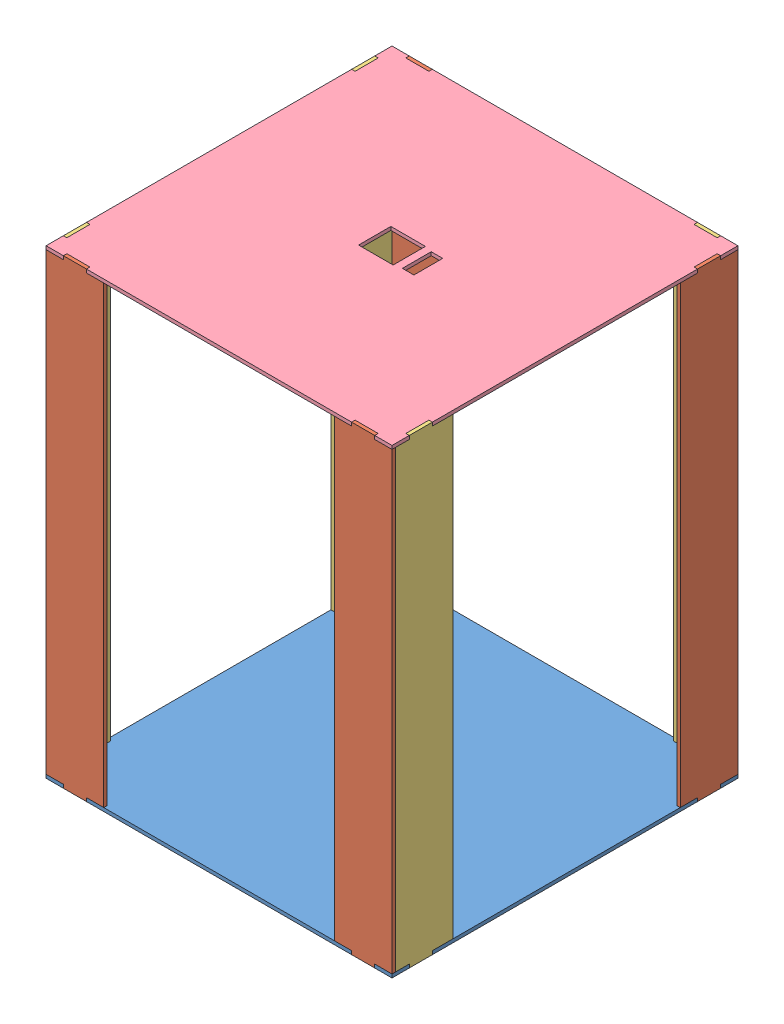
SolidWorks assembly Ensamblaje1Robotica, configuration Predeterminado. Lengths in mm.
Overall size (300 400 300).
10 component instances, 4 part files, 39 mates.
Components (placement in the parent):
- Base_Robotica-1: Base_Robotica [Predeterminado] at (-84.7591 -67.9143 450) size (300 3 300)
- Esquina_Robotica-1: Esquina_Robotica [Predeterminado] at (-84.7591 -64.9143 447) size (50 400 3)
- Esquina_Robotica2-1: Esquina_Robotica2 [Predeterminado] at (-81.7591 -64.9143 153) x (0 0 1) z (-1 0 0) size (50 400 3)
- Esquina_Robotica-2: Esquina_Robotica [Predeterminado] at (-84.7591 -64.9143 150) size (50 400 3)
- Esquina_Robotica2-2: Esquina_Robotica2 [Predeterminado] at (-84.7591 -64.9143 447) x (0 0 -1) z (1 0 0) size (50 400 3)
- Esquina_Robotica-3: Esquina_Robotica [Predeterminado] at (165.2409 -64.9143 447) size (50 400 3)
- Esquina_Robotica-4: Esquina_Robotica [Predeterminado] at (215.2409 -64.9143 150) x (0 0 1) z (-1 0 0) size (50 400 3)
- Esquina_Robotica2-3: Esquina_Robotica2 [Predeterminado] at (212.2409 -64.9143 447) x (0 0 -1) z (1 0 0) size (50 400 3)
- Esquina_Robotica2-4: Esquina_Robotica2 [Predeterminado] at (212.2409 -64.9143 153) x (-1 0 0) z (0 0 -1) size (50 400 3)
- Base_RoboticaSuperior-1: Base_RoboticaSuperior [Predeterminado] at (-84.7591 329.0857 450) size (300 3 300)
Mates (geometry in assembly coordinates):
- Paralelo1: parallel anti-aligned: plane of Base_Robotica-1 through (-69.7591 -64.9143 447) normal (0 0 1); plane of Esquina_Robotica-1 through (-84.7591 -64.9143 447) normal (0 0 -1)
- Coincidente2: coincident anti-aligned: plane of Base_Robotica-1 through (-69.7591 -64.9143 447) normal (0 0 1); plane of Esquina_Robotica-1 through (-84.7591 -64.9143 447) normal (0 0 -1)
- Coincidente3: coincident anti-aligned: plane of Base_Robotica-1 through (-69.7591 -64.9143 450) normal (1 0 0); plane of Esquina_Robotica-1 through (-69.7591 -64.9143 450) normal (-1 0 0)
- Coincidente4: coincident anti-aligned: plane of Base_Robotica-1 through (-84.7591 -64.9143 450) normal (0 1 0); plane of Esquina_Robotica-1 through (-84.7591 -64.9143 450) normal (0 -1 0)
- Paralelo3: parallel anti-aligned: plane of Base_Robotica-1 through (-81.7591 -64.9143 165) normal (-1 0 0); plane of Esquina_Robotica2-1 through (-81.7591 -64.9143 153) normal (1 0 0)
- Coincidente9: coincident anti-aligned: plane of Base_Robotica-1 through (-81.7591 -64.9143 165) normal (-1 0 0); plane of Esquina_Robotica2-1 through (-81.7591 -64.9143 153) normal (1 0 0)
- Coincidente10: coincident anti-aligned: plane of Base_Robotica-1 through (-84.7591 -64.9143 165) normal (0 0 1); plane of Esquina_Robotica2-1 through (-84.7591 -64.9143 165) normal (0 0 -1)
- Coincidente11: coincident anti-aligned: plane of Base_Robotica-1 through (-84.7591 -64.9143 450) normal (0 1 0); plane of Esquina_Robotica2-1 through (-84.7591 -64.9143 153) normal (0 -1 0)
- Paralelo4: parallel anti-aligned: plane of Base_Robotica-1 through (-69.7591 -64.9143 153) normal (0 0 -1); plane of Esquina_Robotica-2 through (-84.7591 -64.9143 153) normal (0 0 1)
- Coincidente13: coincident anti-aligned: plane of Base_Robotica-1 through (-69.7591 -64.9143 153) normal (0 0 -1); plane of Esquina_Robotica-2 through (-84.7591 -64.9143 153) normal (0 0 1)
- Coincidente14: coincident anti-aligned: plane of Base_Robotica-1 through (-49.7591 -64.9143 153) normal (-1 0 0); plane of Esquina_Robotica-2 through (-49.7591 -64.9143 153) normal (1 0 0)
- Coincidente16: coincident anti-aligned: plane of Esquina_Robotica2-1 through (-84.7591 -64.9143 153) normal (0 0 -1); plane of Esquina_Robotica-2 through (-84.7591 -64.9143 153) normal (0 0 1)
- Coincidente17: coincident anti-aligned: plane of Base_Robotica-1 through (-84.7591 -64.9143 450) normal (0 1 0); plane of Esquina_Robotica-2 through (-84.7591 -64.9143 153) normal (0 -1 0)
- Paralelo5: parallel anti-aligned: plane of Base_Robotica-1 through (-81.7591 -64.9143 435) normal (-1 0 0); plane of Esquina_Robotica2-2 through (-81.7591 -64.9143 447) normal (1 0 0)
- Coincidente19: coincident anti-aligned: plane of Base_Robotica-1 through (-81.7591 -64.9143 435) normal (-1 0 0); plane of Esquina_Robotica2-2 through (-81.7591 -64.9143 447) normal (1 0 0)
- Coincidente22: coincident anti-aligned: plane of Base_Robotica-1 through (-81.7591 -64.9143 415) normal (0 0 1); plane of Esquina_Robotica2-2 through (-81.7591 -64.9143 415) normal (0 0 -1)
- Coincidente23: coincident anti-aligned: plane of Esquina_Robotica-1 through (-84.7591 -64.9143 447) normal (0 0 -1); plane of Esquina_Robotica2-2 through (-81.7591 -64.9143 447) normal (0 0 1)
- Coincidente24: coincident anti-aligned: plane of Base_Robotica-1 through (-84.7591 -64.9143 450) normal (0 1 0); plane of Esquina_Robotica2-2 through (-81.7591 -64.9143 447) normal (0 -1 0)
- Paralelo7: parallel anti-aligned: plane of Base_Robotica-1 through (200.2409 -64.9143 447) normal (0 0 1); plane of Esquina_Robotica-3 through (165.2409 -64.9143 447) normal (0 0 -1)
- Coincidente26: coincident anti-aligned: plane of Base_Robotica-1 through (200.2409 -64.9143 447) normal (0 0 1); plane of Esquina_Robotica-3 through (165.2409 -64.9143 447) normal (0 0 -1)
- Coincidente27: coincident anti-aligned: plane of Base_Robotica-1 through (200.2409 -64.9143 450) normal (-1 0 0); plane of Esquina_Robotica-3 through (200.2409 -64.9143 450) normal (1 0 0)
- Coincidente28: coincident anti-aligned: plane of Base_Robotica-1 through (-84.7591 -64.9143 450) normal (0 1 0); plane of Esquina_Robotica-3 through (165.2409 -64.9143 450) normal (0 -1 0)
- Coincidente29: coincident anti-aligned: plane of Base_Robotica-1 through (212.2409 -64.9143 165) normal (1 0 0); plane of Esquina_Robotica-4 through (212.2409 -64.9143 150) normal (-1 0 0)
- Paralelo8: parallel anti-aligned: plane of Base_Robotica-1 through (212.2409 -64.9143 165) normal (1 0 0); plane of Esquina_Robotica-4 through (212.2409 -64.9143 150) normal (-1 0 0)
- Coincidente31: coincident anti-aligned: plane of Base_Robotica-1 through (212.2409 -64.9143 185) normal (0 0 -1); plane of Esquina_Robotica-4 through (212.2409 -64.9143 185) normal (0 0 1)
- Coincidente32: coincident anti-aligned: plane of Base_Robotica-1 through (-84.7591 -64.9143 450) normal (0 1 0); plane of Esquina_Robotica-4 through (212.2409 -64.9143 150) normal (0 -1 0)
- Paralelo9: parallel anti-aligned: plane of Base_Robotica-1 through (212.2409 -64.9143 435) normal (1 0 0); plane of Esquina_Robotica2-3 through (212.2409 -64.9143 447) normal (-1 0 0)
- Coincidente34: coincident anti-aligned: plane of Base_Robotica-1 through (212.2409 -64.9143 435) normal (1 0 0); plane of Esquina_Robotica2-3 through (212.2409 -64.9143 447) normal (-1 0 0)
- Coincidente35: coincident anti-aligned: plane of Esquina_Robotica-3 through (165.2409 -64.9143 447) normal (0 0 -1); plane of Esquina_Robotica2-3 through (215.2409 -64.9143 447) normal (0 0 1)
- Coincidente36: coincident anti-aligned: plane of Base_Robotica-1 through (215.2409 -64.9143 435) normal (0 0 -1); plane of Esquina_Robotica2-3 through (215.2409 -64.9143 435) normal (0 0 1)
- Coincidente37: coincident: plane of Base_Robotica-1 through (-84.7591 -64.9143 450) normal (0 1 0); line of Esquina_Robotica2-3 through (215.2409 -64.9143 447) axis (0 0 -1)
- Paralelo12: parallel anti-aligned: plane of Base_Robotica-1 through (180.2409 -64.9143 150) normal (0 0 -1); plane of Esquina_Robotica2-4 through (212.2409 -64.9143 153) normal (0 0 1)
- Coincidente43: coincident anti-aligned: plane of Base_Robotica-1 through (200.2409 -64.9143 153) normal (0 0 -1); plane of Esquina_Robotica2-4 through (212.2409 -64.9143 153) normal (0 0 1)
- Coincidente44: coincident: plane of Esquina_Robotica-4 through (212.2409 -64.9143 150) normal (-1 0 0); line of Esquina_Robotica2-4 through (212.2409 329.0857 150) axis (0 -1 0)
- Coincidente45: coincident anti-aligned: plane of Base_Robotica-1 through (-84.7591 -64.9143 450) normal (0 1 0); plane of Esquina_Robotica2-4 through (212.2409 -64.9143 150) normal (0 -1 0)
- Paralelo13: parallel anti-aligned: plane of Esquina_Robotica-1 through (-84.7591 332.0857 450) normal (0 1 0); plane of Base_RoboticaSuperior-1 through (-84.7591 329.0857 450) normal (0 -1 0)
- Coincidente47: coincident anti-aligned: plane of Esquina_Robotica-1 through (-84.7591 -64.9143 447) normal (0 0 -1); plane of Base_RoboticaSuperior-1 through (-69.7591 332.0857 447) normal (0 0 1)
- Coincidente48: coincident anti-aligned: plane of Esquina_Robotica-1 through (-49.7591 -64.9143 450) normal (1 0 0); plane of Base_RoboticaSuperior-1 through (-49.7591 332.0857 447) normal (-1 0 0)
- Coincidente49: coincident anti-aligned: plane of Esquina_Robotica-1 through (-84.7591 329.0857 450) normal (0 1 0); plane of Base_RoboticaSuperior-1 through (-84.7591 329.0857 450) normal (0 -1 0)
